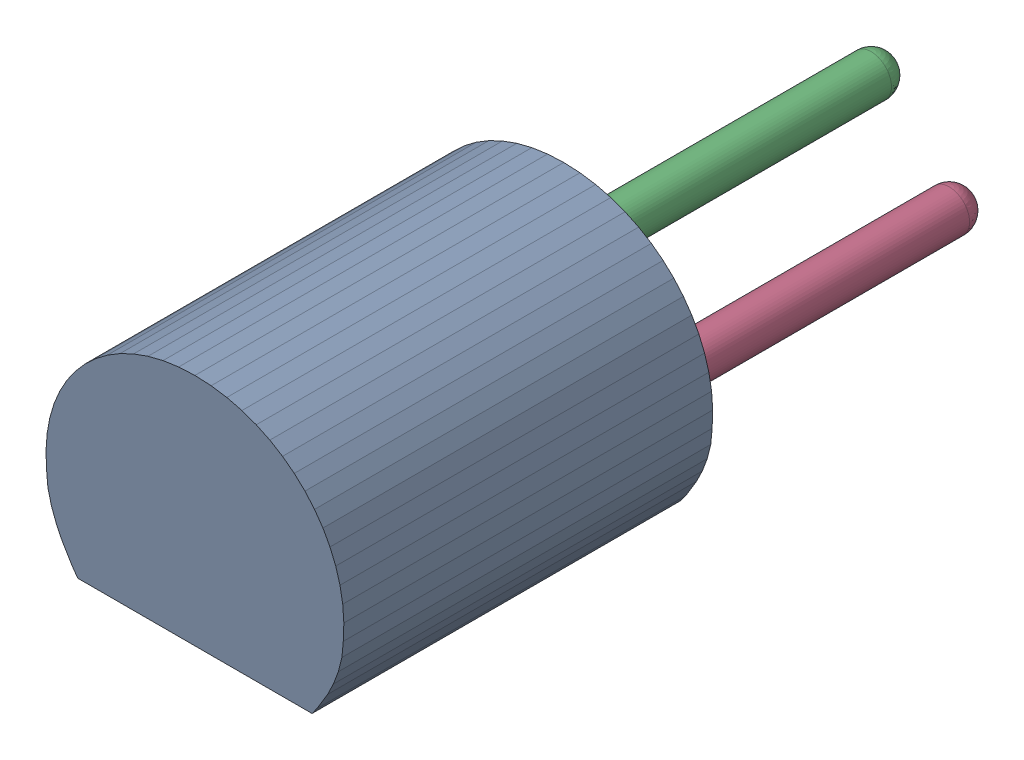
SolidWorks assembly Q1, configuration Défaut. Lengths in mm.
Overall size (4.85 3.81 11.33).
5 component instances, 4 part files, 0 mates.
Components (placement in the parent):
- Open CASCADE STEP translator 6.8 1.25.1-1: Open CASCADE STEP translator 6.8 1.25.1 [Défaut] at origin size (4.85 3.81 11.33)
  - Body_1_12-1: Body_1_12 [Défaut] at origin size (4.85 3.81 6)
  - Pin_1_9-1: Pin_1_9 [Défaut] at (-1.27 -1.27 0) x (0 -1 0) z (0 0 1) size (0.66 0.66 8.66)
  - Pin_2_9-1: Pin_2_9 [Défaut] at (-1.27 1.27 0) x (0 -1 0) z (0 0 1) size (0.66 0.66 8.66)
  - Pin_3_5-1: Pin_3_5 [Défaut] at (1.27 1.27 0) x (0 -1 0) z (0 0 1) size (0.66 0.66 8.66)
